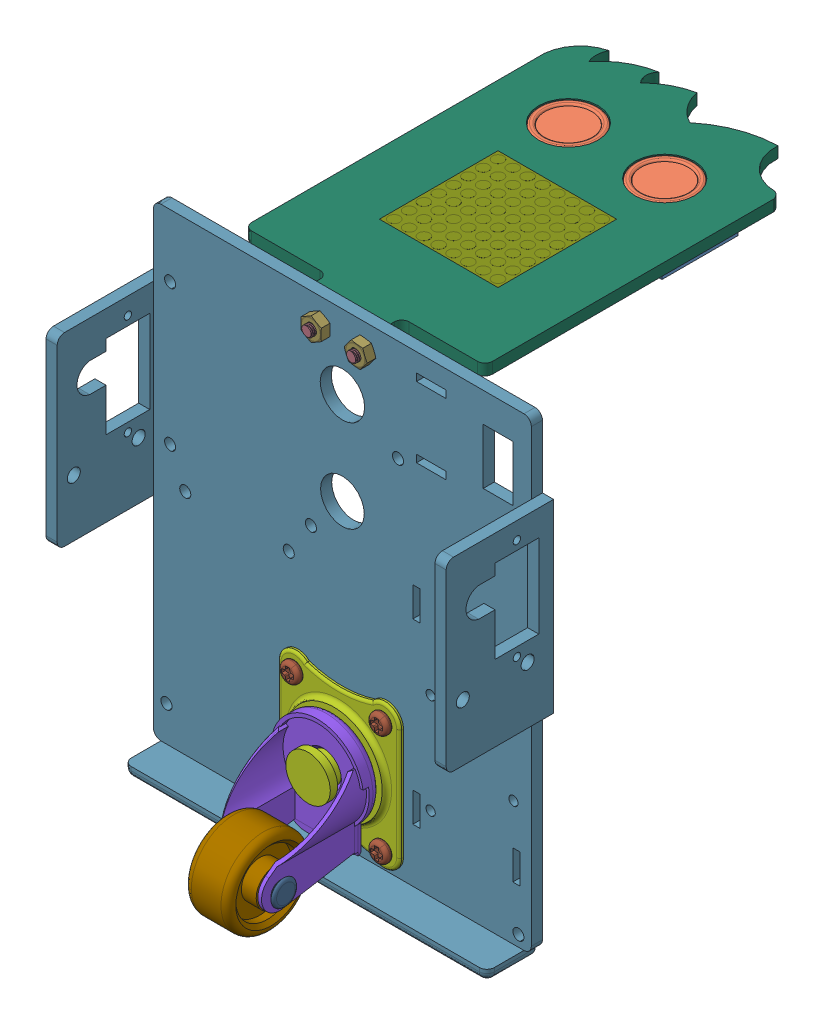
SolidWorks assembly DYOR_3D_LM, configuration Predeterminado. Lengths in mm.
Overall size (108 131.4 135.99).
36 component instances, 16 part files, 17 mates.
Components (placement in the parent):
- HC-SR04 Ping Sensor-1: HC-SR04 Ping Sensor [Default] at (9.418 28.7888 -61.4611) x (0 0 -1) z (0 1 0) size (25.18 45 18.07)
  - PCB-1: PCB [Default] at origin size (20.5 45 1.75)
  - Transducer-1: Transducer [Default] at (0 -13 13.25) x (1 0 0) z (0 -1 0) size (15.88 12 15.88)
  - Transducer-2: Transducer [Default] at (0 13 13.25) x (1 0 0) z (0 -1 0) size (15.88 12 15.88)
  - 3 Pin Header 90 Degree-1: 3 Pin Header 90 Degree [Default] at (8.4275 0 -1.25) x (-1 0 0) z (0 -1 0) size (8 7.82 10)
  - 14 Pin SMT-1: 14 Pin SMT [Default] at (-0.35 -18.5 -0.85) x (0 -1 0) z (1 0 0) size (6 1.6 8.8)
  - 14 Pin SMT-2: 14 Pin SMT [Default] at (0 -0.3826 -0.85) x (1 0 0) z (0 1 0) size (6 1.6 8.8)
  - 14 Pin SMT-3: 14 Pin SMT [Default] at (0 17.5274 -0.85) x (1 0 0) z (0 1 0) size (6 1.6 8.8)
  - Cap1 SMT-1: Cap1 SMT [Default] at (-1.755 7.4774 -0.9689) x (0 1 0) z (-1 0 0) size (4.5 1.84 1.75)
  - Cap1 SMT-2: Cap1 SMT [Default] at (6.835 7.4774 -0.9689) x (0 1 0) z (-1 0 0) size (4.5 1.84 1.75)
  - Cap1 SMT-3: Cap1 SMT [Default] at (-6.835 7.4774 -0.9689) x (0 1 0) z (-1 0 0) size (4.5 1.84 1.75)
  - Cap1 SMT-4: Cap1 SMT [Default] at (4.295 7.4774 -0.9689) x (0 1 0) z (-1 0 0) size (4.5 1.84 1.75)
  - Cap1 SMT-5: Cap1 SMT [Default] at (1.755 7.4774 -0.9689) x (0 1 0) z (-1 0 0) size (4.5 1.84 1.75)
  - Cap1 SMT-6: Cap1 SMT [Default] at (-4.295 7.4774 -0.9689) x (0 1 0) z (-1 0 0) size (4.5 1.84 1.75)
  - HC-SR04 Crystal-1: HC-SR04 Crystal [Default] at (-8.3 0 1.75) x (0 -1 0) z (0 0 1) size (10 3.5 2.7)
- CA-1: CA [Predeterminado] at (-2.207 18.0036 0) size (33 45.94 43.2)
  - Caster Wheel-1: Caster Wheel [Default] at (57.6387 -78.841 57.7572) x (0 1 0) z (-1 0 0) size (45.94 37.59 33)
    - caster holder-1: caster holder [Default] at (-24.0751 44.7184 29.5137) x (1 0 0) z (0 0 -1) size (39 9.27 33)
    - holder-1: holder [Default] at (-1.5751 42.9484 46.0137) x (0 0 1) z (1 0 0) size (25 28.07 31.31)
    - caster wheel-1: caster wheel [Default] at (-15.6961 19.9484 46.0137) x (0.997275 0.073773 0) z (0 0 1) size (23 23 14)
    - Part4-1: Part4 [Default] at (-15.6961 19.9484 55.0137) x (-0.978448 0.206495 0) z (0 0 -1) size (7 7 20)
  - M3x6 Philips Screw-1: M3x6 Philips Screw [Predeterminado] at (23.625 -65.4161 13.5389) size (5.3 5.3 7.81)
  - M3x6 Philips Screw-2: M3x6 Philips Screw [Predeterminado] at (-0.375 -65.4161 13.5389) size (5.3 5.3 7.81)
  - M3x6 Philips Screw-3: M3x6 Philips Screw [Predeterminado] at (-0.375 -95.4161 13.5389) size (5.3 5.3 7.81)
  - M3x6 Philips Screw-4: M3x6 Philips Screw [Predeterminado] at (23.625 -95.4161 13.5389) size (5.3 5.3 7.81)
  - M3 Nut-1: M3 Nut [Predeterminado] at (23.625 -65.4161 11.0389) size (6.27 6.27 2.71)
  - M3 Nut-2: M3 Nut [Predeterminado] at (-0.375 -65.4161 11.0389) size (6.27 6.27 2.71)
  - M3 Nut-3: M3 Nut [Predeterminado] at (-0.375 -95.4161 11.0389) size (6.27 6.27 2.71)
  - M3 Nut-4: M3 Nut [Predeterminado] at (23.625 -95.4161 11.0389) size (6.27 6.27 2.71)
- M3x10 Philips Screw-2: M3x10 Philips Screw [Predeterminado] at (3.418 36.0388 6.1705) x (-0.582954 -0.812505 0) z (0 0 -1) size (5.3 5.3 11.8)
- M3x10 Philips Screw-3: M3x10 Philips Screw [Predeterminado] at (15.418 36.0388 6.1705) x (-0.89856 -0.438851 0) z (0 0 -1) size (5.3 5.3 11.8)
- M3 Nut-1: M3 Nut [Predeterminado] at (3.418 36.0388 16.5389) size (6.27 6.27 2.71)
- M3 Nut-2: M3 Nut [Predeterminado] at (15.418 36.0388 11.0389) x (-0.923728 -0.383049 0) z (0 0 -1) size (6.27 6.27 2.71)
- Base-1: Base [Predeterminado] at (60.418 -80.9125 12.5389) size (108 128.45 29)
- Front_LM-1: Front_LM [Predeterminado] at (-49.2809 42.5388 -46.4821) x (1 0 0) z (0 1 0) size (65 95.41 11)
- max7219_compact_board-1: max7219_compact_board [Predeterminado] at (15.918 28.3388 -29.4611) x (1 0 0) z (0 1 0) size (34 32 21.83)
Mates (geometry in assembly coordinates):
- Concéntrica15: concentric: circle of CA-1/Caster Wheel-1/caster holder-1; circle of Base-1
- Coincidente14: coincident: plane of CA-1/M3 Nut-4 through (21.418 -77.4125 9.5389) normal (0 0 1); plane of Base-1 through (-39.582 40.5388 9.5389) normal (0 0 -1)
- Concéntrica16: concentric: circle of CA-1/M3 Nut-1; circle of Base-1
- Coincidente16: coincident: plane of Base-1 through (-39.582 40.5388 9.5389) normal (0 0 -1); plane of Front_LM-1 through (-0.582 39.5388 9.5389) normal (0 0 1)
- Paralelo1: parallel: plane of Base-1 through (-39.582 42.5388 9.5389) normal (0 1 0); plane of Front_LM-1 through (-2.582 42.5388 8.5389) normal (0 1 0)
- Concéntrica18: concentric: circle of HC-SR04 Ping Sensor-1/Transducer-1; circle of Front_LM-1
- Concéntrica19: concentric: circle of HC-SR04 Ping Sensor-1/Transducer-2; circle of Front_LM-1
- Coincidente19: coincident: plane of HC-SR04 Ping Sensor-1/Transducer-1 through (22.418 42.5388 -69.4011) normal (0 1 0); plane of Front_LM-1 through (-2.582 42.5388 8.5389) normal (0 1 0)
- Coincidente20: coincident: plane of Front_LM-1 through (25.418 39.5388 -45.4611) normal (0 0 1); plane of max7219_compact_board-1 through (-6.582 42.5388 -45.4611) normal (0 0 -1)
- Coincidente21: coincident: plane of Front_LM-1 through (25.418 39.5388 -13.4611) normal (-1 0 0); plane of max7219_compact_board-1 through (25.418 42.5388 -45.4611) normal (1 0 0)
- Coincidente22: coincident: plane of Front_LM-1 through (-2.582 42.5388 8.5389) normal (0 1 0); plane of max7219_compact_board-1 through (15.918 42.5388 -29.4611) normal (0 1 0)
- Coincidente23: coincident: plane of M3x10 Philips Screw-3 through (14.7159 37.4765 6.1705) normal (0 0 1); plane of Front_LM-1 through (19.418 31.5388 6.1705) normal (0 0 -1)
- Coincidente24: coincident: plane of M3x10 Philips Screw-2 through (2.118 36.9715 6.1705) normal (0 0 1); plane of Front_LM-1 through (19.418 31.5388 6.1705) normal (0 0 -1)
- Coincidente26: coincident: plane of M3 Nut-2 through (15.418 36.0388 12.5389) normal (0 0 -1); plane of Base-1 through (-39.582 40.5388 12.5389) normal (0 0 1)
- Coincidente27: coincident: plane of M3 Nut-1 through (3.418 36.0388 12.5389) normal (0 0 -1); plane of Base-1 through (-39.582 40.5388 12.5389) normal (0 0 1)
- Concéntrica22: concentric: circle of M3 Nut-1; circle of Base-1
- Concéntrica23: concentric: circle of M3 Nut-2; circle of Base-1
